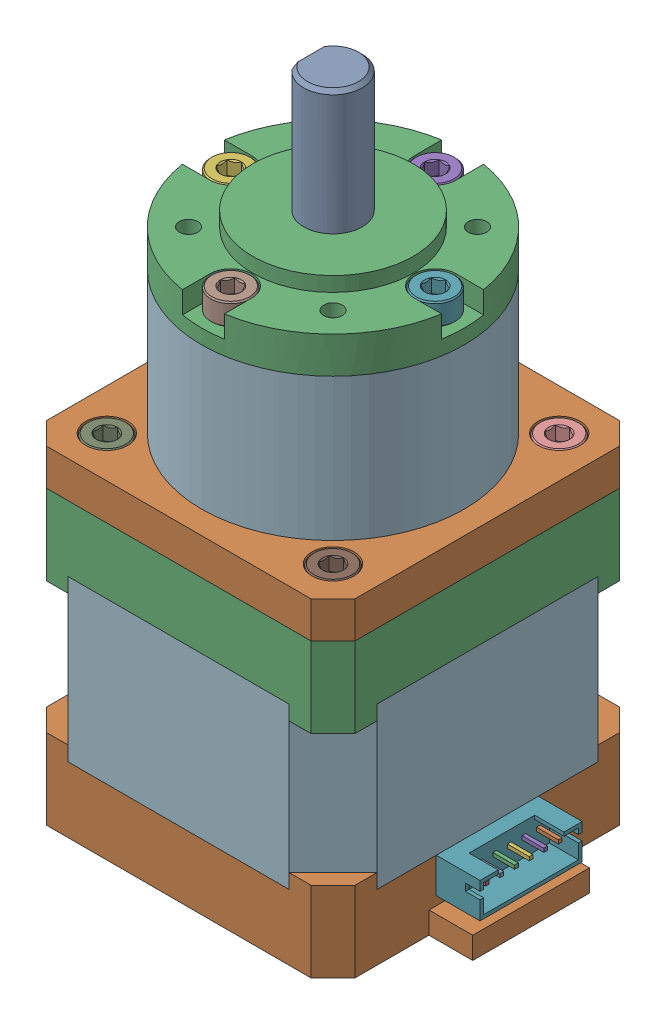
SolidWorks assembly Nema 17 40mm 5_1 Planetary Gearbox, configuration Default. Lengths in mm.
Overall size (48.3 88.5 42.3).
30 component instances, 12 part files, 0 mates.
Components (placement in the parent):
- Nema 17 40mm.step-1: Nema 17 40mm.step [Default] at origin size (48.3 64 42.3)
  - JST 2.0 PH - 6 Pin.step-1: JST 2.0 PH - 6 Pin.step [Default] at (21.15 9 -7) x (0 0 1) z (0 1 0) size (14 9.4 4.8)
    - Pin.step-1: Pin.step [Default] at origin size (10.5 8.4 0.5)
    - JST 2.0 PH - 6 Pin-0.step-1: JST 2.0 PH - 6 Pin-0.step [Default] at origin size (14 6 4.8)
  - M3 x 15mm.step-1: M3 x 15mm.step [Default] at (15.5 18 15.5) x (1 0 0) z (0 1 0) size (5.5 5.5 18)
    - M3 x 15mm-1.step-1: M3 x 15mm-1.step [Default] at origin size (5.5 5.5 18)
  - M3 x 15mm.step-2: M3 x 15mm.step [Default] at (15.5 18 -15.5) x (1 0 0) z (0 1 0) size (5.5 5.5 18)
    - M3 x 15mm-1.step-1: M3 x 15mm-1.step [Default] at origin size (5.5 5.5 18)
  - M3 x 15mm.step-3: M3 x 15mm.step [Default] at (-15.5 18 15.5) x (1 0 0) z (0 1 0) size (5.5 5.5 18)
    - M3 x 15mm-1.step-1: M3 x 15mm-1.step [Default] at origin size (5.5 5.5 18)
  - M3 x 15mm.step-4: M3 x 15mm.step [Default] at (-15.5 18 -15.5) x (1 0 0) z (0 1 0) size (5.5 5.5 18)
    - M3 x 15mm-1.step-1: M3 x 15mm-1.step [Default] at origin size (5.5 5.5 18)
  - Mid.step-1: Mid.step [Default] at origin size (42.3 22 42.3)
  - Shaft.step-1: Shaft.step [Default] at origin size (5 24 5)
  - Nema 17 40mm-2.step-1: Nema 17 40mm-2.step [Default] at origin size (48.3 11 42.3)
  - Nema 17 40mm-3.step-1: Nema 17 40mm-3.step [Default] at origin size (42.3 13 42.3)
- Nema 17 5_1 Planetary Gearbox.step-1: Nema 17 5_1 Planetary Gearbox.step [Default] at (0 -8 0) size (42.3 52.5 42.3)
  - Screws.step-1: Screws.step [Default] at origin size (36.5 33.5 36.5)
    - M3 x 6mm.step-1: M3 x 6mm.step [Default] at (-15.5 44 -15.5) x (1 0 0) z (0 -1 0) size (5.5 5.5 9)
    - M3 x 6mm.step-2: M3 x 6mm.step [Default] at (0 68.5 -14) x (0 0 1) z (0 -1 0) size (5.5 5.5 9)
    - M3 x 6mm.step-3: M3 x 6mm.step [Default] at (-14 68.5 0) x (1 0 0) z (0 -1 0) size (5.5 5.5 9)
    - M3 x 6mm.step-4: M3 x 6mm.step [Default] at (14 68.5 0) x (-1 0 0) z (0 -1 0) size (5.5 5.5 9)
    - M3 x 6mm.step-5: M3 x 6mm.step [Default] at (0 68.5 14) x (0 0 -1) z (0 -1 0) size (5.5 5.5 9)
    - M3 x 6mm.step-6: M3 x 6mm.step [Default] at (-15.5 44 15.5) x (1 0 0) z (0 -1 0) size (5.5 5.5 9)
    - M3 x 6mm.step-7: M3 x 6mm.step [Default] at (15.5 44 -15.5) x (1 0 0) z (0 -1 0) size (5.5 5.5 9)
    - M3 x 6mm.step-8: M3 x 6mm.step [Default] at (15.5 44 15.5) x (1 0 0) z (0 -1 0) size (5.5 5.5 9)
  - Mid_1.step-1: Mid_1.step [Default] at origin size (36 19.5 36)
  - Shaft_1.step-1: Shaft_1.step [Default] at origin size (8 19 8)
  - Nema 17 5_1 Planetary Gearbox-4.step-1: Nema 17 5_1 Planetary Gearbox-4.step [Default] at origin size (42.3 5 42.3)
  - Nema 17 5_1 Planetary Gearbox-5.step-1: Nema 17 5_1 Planetary Gearbox-5.step [Default] at origin size (36 7 36)
